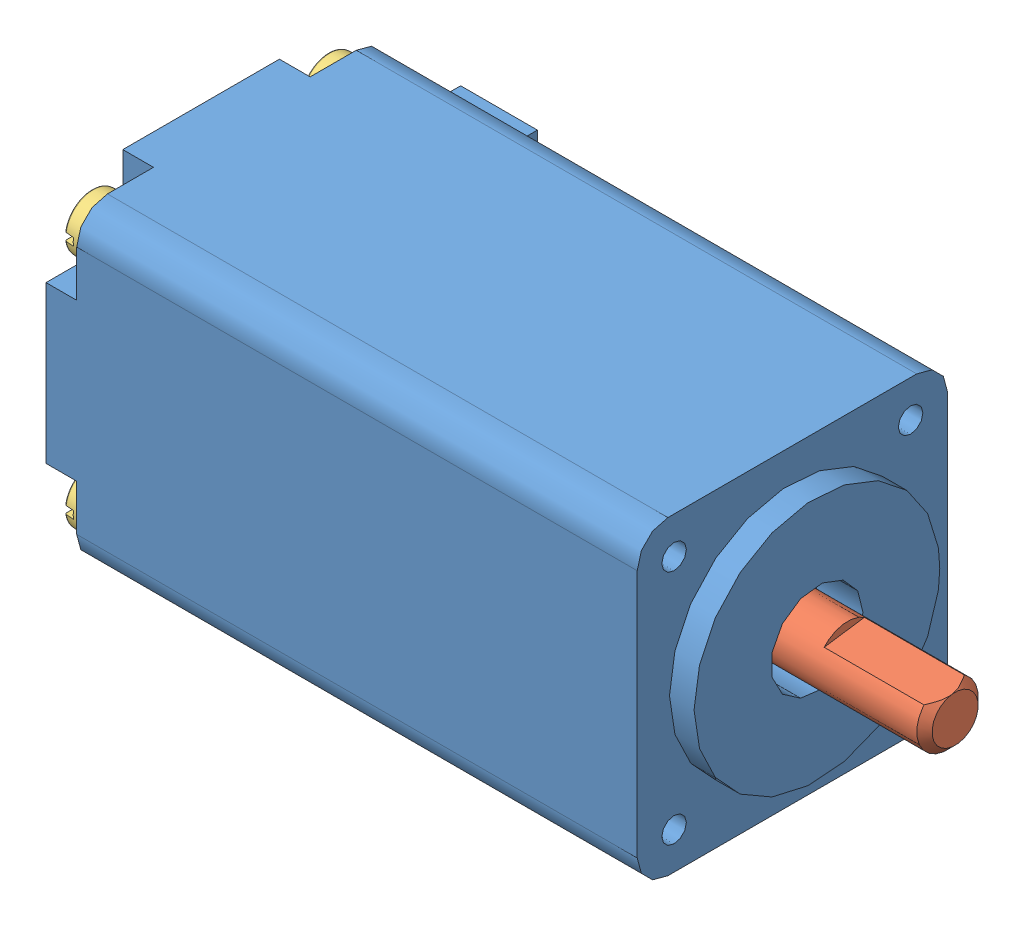
SolidWorks assembly Motor_NEMA8_Stepper, configuration По умолчанию. Lengths in mm.
Overall size (49.1 20.2 23.7).
6 component instances, 3 part files, 10 mates.
Components (placement in the parent):
- Stator-1: Stator [По умолчанию] at (-20.6518 -8.7619 9.3639) size (40.1 20.2 23.7)
- Rotor-1: Rotor [По умолчанию] at (-15.6518 1.3381 -0.7361) x (0 0.143607 -0.989635) z (1 0 0) size (4 4 44.1)
- slotted cheese head screw_din-2: slotted cheese head screw_din [ISO 1207 - M2 x 20 --- 20N] at (-20.0518 9.0381 -8.4361) size (21.4 3.8 3.8)
- slotted cheese head screw_din-3: slotted cheese head screw_din [ISO 1207 - M2 x 20 --- 20N] at (-20.0518 9.0381 6.9639) size (21.4 3.8 3.8)
- slotted cheese head screw_din-4: slotted cheese head screw_din [ISO 1207 - M2 x 20 --- 20N] at (-20.0518 -6.3619 6.9639) size (21.4 3.8 3.8)
- slotted cheese head screw_din-5: slotted cheese head screw_din [ISO 1207 - M2 x 20 --- 20N] at (-20.0518 -6.3619 -8.4361) size (21.4 3.8 3.8)
Mates (geometry in assembly coordinates):
- Совпадение1: coincident anti-aligned: plane of Stator-1 through (-15.1518 1.3381 -0.7361) normal (-1 0 0); circle of Rotor-1
- Концентричный1: concentric anti-aligned: cylinder of Stator-1 through (-20.6518 1.3381 -0.7361) axis (1 0 0) radius 2; cylinder of Rotor-1 through (28.4482 1.3381 -0.7361) axis (-1 0 0) radius 2
- Концентричный2: concentric aligned: cylinder of Stator-1 through (-18.6518 9.0381 -8.4361) axis (-1 0 0) radius 0.8; cylinder of slotted cheese head screw_din-2 through (-45.4518 9.0381 -8.4361) axis (-1 0 0) radius 1
- Совпадение2: coincident anti-aligned: plane of Stator-1 through (-18.6518 9.4381 -8.8361) normal (-1 0 0); plane of slotted cheese head screw_din-2 through (-18.6518 10.0381 -8.4361) normal (1 0 0)
- Концентричный3: concentric aligned: cylinder of Stator-1 through (-18.6518 9.0381 6.9639) axis (-1 0 0) radius 0.8; cylinder of slotted cheese head screw_din-3 through (-45.4518 9.0381 6.9639) axis (-1 0 0) radius 1
- Совпадение3: coincident anti-aligned: plane of Stator-1 through (-18.6518 9.4381 7.3639) normal (-1 0 0); plane of slotted cheese head screw_din-3 through (-18.6518 10.0381 6.9639) normal (1 0 0)
- Концентричный4: concentric aligned: cylinder of Stator-1 through (-18.6518 -6.3619 6.9639) axis (-1 0 0) radius 0.8; cylinder of slotted cheese head screw_din-4 through (-45.4518 -6.3619 6.9639) axis (-1 0 0) radius 1
- Совпадение4: coincident anti-aligned: plane of Stator-1 through (-18.6518 -6.7619 7.3639) normal (-1 0 0); plane of slotted cheese head screw_din-4 through (-18.6518 -5.3619 6.9639) normal (1 0 0)
- Концентричный5: concentric aligned: cylinder of Stator-1 through (-18.6518 -6.3619 -8.4361) axis (-1 0 0) radius 0.8; cylinder of slotted cheese head screw_din-5 through (-45.4518 -6.3619 -8.4361) axis (-1 0 0) radius 1
- Совпадение5: coincident anti-aligned: plane of Stator-1 through (-18.6518 -6.7619 -8.8361) normal (-1 0 0); plane of slotted cheese head screw_din-5 through (-18.6518 -5.3619 -8.4361) normal (1 0 0)
